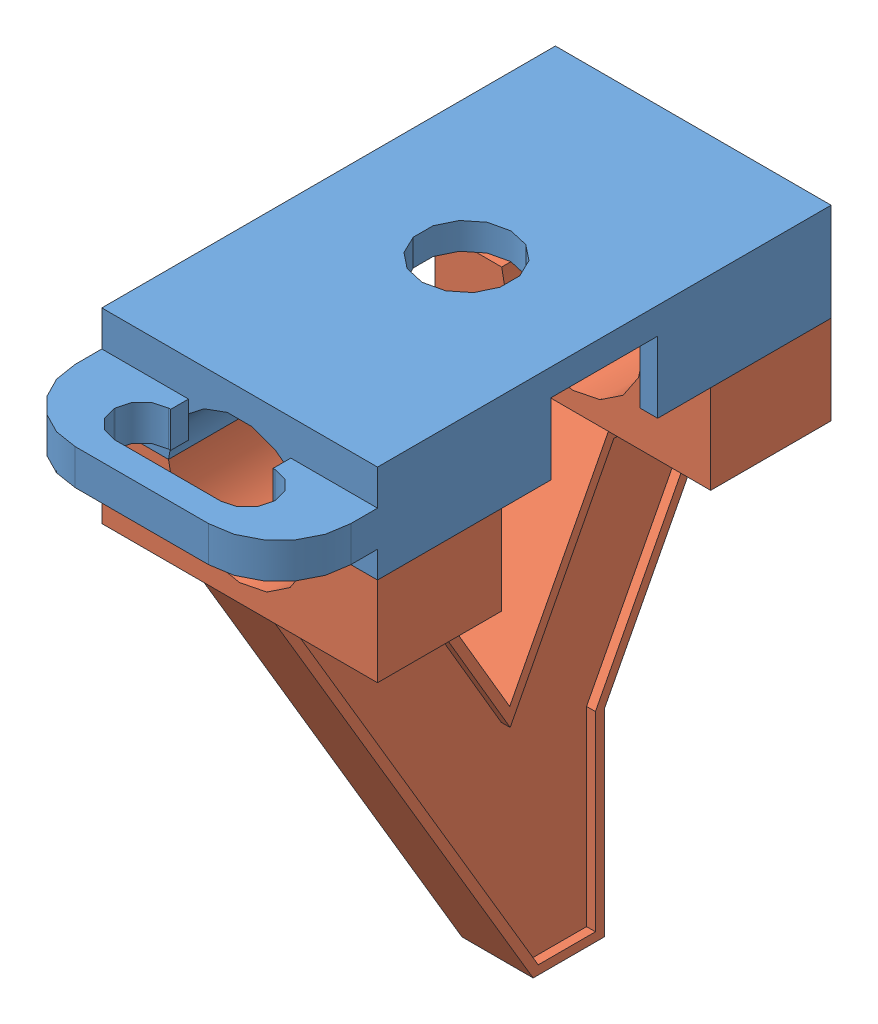
SolidWorks assembly Assem1, configuration По умолчанию. Lengths in mm.
Overall size (31 70 62).
2 component instances, 2 part files, 3 mates.
Components (placement in the parent):
- motorhandle-top-1: motorhandle-top [По умолчанию] at (21.0775 49.34 37.2318) size (31 11.52 62)
- motorhandle-bottom-1: motorhandle-bottom [По умолчанию] at (21.0775 28.34 37.2318) x (0 0 -1) z (1 0 0) size (51 59 31)
Mates (geometry in assembly coordinates):
- Concentric1: concentric: circle of motorhandle-top-1; circle of motorhandle-bottom-1
- Parallel4: parallel: plane of motorhandle-top-1 through (21.0775 38.34 37.2318) normal (0 -1 0); plane of motorhandle-bottom-1 through (21.0775 38.34 88.2318) normal (0 1 0)
- Coincident2: coincident aligned: plane of motorhandle-top-1 through (36.5775 38.34 62.7318) normal (0 0 1); plane of motorhandle-bottom-1 through (5.5775 38.34 62.7318) normal (0 0 1)
